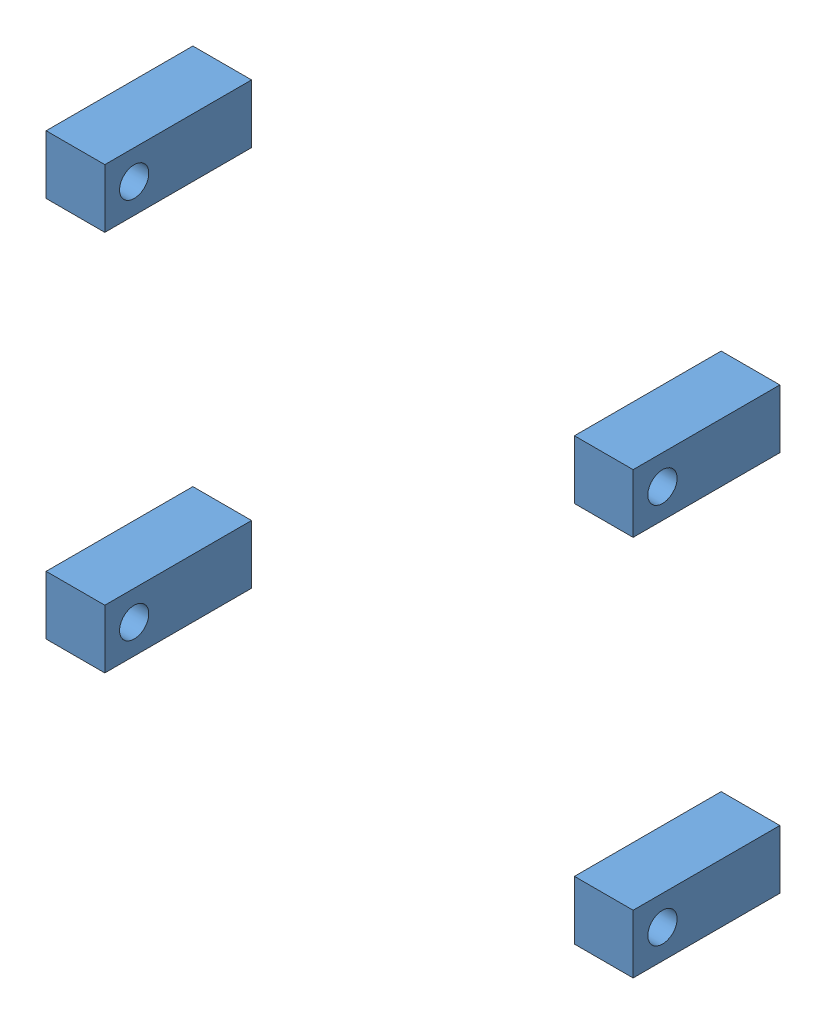
SolidWorks assembly scoring mech v22, configuration Default. Lengths in mm.
Overall size (254 190.5 63.5).
4 component instances, 1 part files, 8 mates.
Components (placement in the parent):
- mech v2 part 1-7: mech v2 part 1 [Default] at (-2.0934 -8.1358 34.7068) size (25.4 25.4 63.5)
- mech v2 part 1-9: mech v2 part 1 [Default] at (-2.0934 156.9642 34.7068) size (25.4 25.4 63.5)
- mech v2 part 1-10: mech v2 part 1 [Default] at (226.5066 156.9642 34.7068) size (25.4 25.4 63.5)
- mech v2 part 1-11: mech v2 part 1 [Default] at (226.5066 -8.1358 34.7068) size (25.4 25.4 63.5)
Mates (geometry in assembly coordinates):
- Coincident17: coincident aligned: plane of mech v2 part 1-9 through (-2.0934 208.8178 98.2068) normal (0 0 1); plane of mech v2 part 1-10 through (226.5066 208.8178 98.2068) normal (0 0 1)
- Coincident18: coincident aligned: plane of mech v2 part 1-10 through (222.1421 216.46 98.2068) normal (1 0 0); plane of mech v2 part 1-11 through (222.1421 51.36 98.2068) normal (1 0 0)
- Coincident19: coincident aligned: plane of mech v2 part 1-10 through (226.5066 208.8178 98.2068) normal (0 0 1); plane of mech v2 part 1-11 through (226.5066 43.7178 98.2068) normal (0 0 1)
- Coincident20: coincident aligned: plane of mech v2 part 1-7 through (-2.0934 -8.1358 98.2068) normal (0 0 1); plane of mech v2 part 1-11 through (226.5066 43.7178 98.2068) normal (0 0 1)
- Coincident21: coincident aligned: plane of mech v2 part 1-7 through (-6.4579 -0.4936 98.2068) normal (1 0 0); plane of mech v2 part 1-9 through (-6.4579 216.46 98.2068) normal (1 0 0)
- Distance8: distance = 254 mm anti-aligned: plane of mech v2 part 1-10 through (222.1421 164.6064 98.2068) normal (1 0 0); plane of mech v2 part 1-9 through (-31.8579 164.6064 98.2068) normal (-1 0 0)
- Distance9: distance = 139.7 mm anti-aligned: plane of mech v2 part 1-10 through (222.1421 164.6064 98.2068) normal (0 -1 0); plane of mech v2 part 1-11 through (222.1421 24.9064 98.2068) normal (0 1 0)
- Coincident25: coincident aligned: plane of mech v2 part 1-7 through (-6.4579 24.9064 98.2068) normal (0 1 0); plane of mech v2 part 1-11 through (222.1421 24.9064 98.2068) normal (0 1 0)
